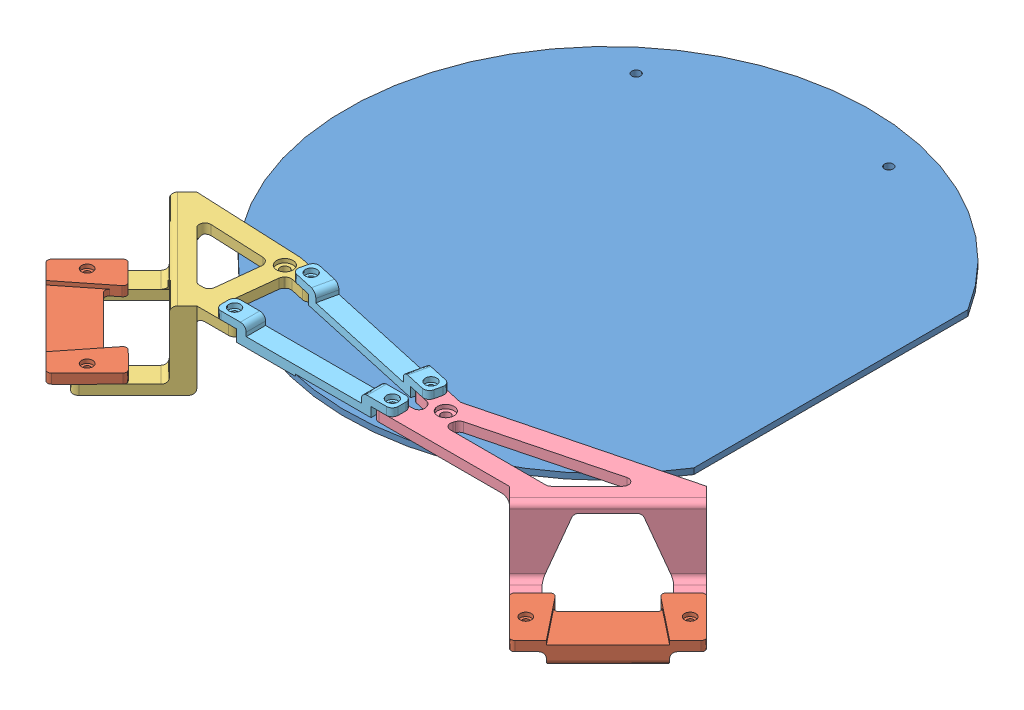
SolidWorks assembly CAMERA_MOUNT_ASSEMBLY, configuration Default. Lengths in mm.
Overall size (340.83 45.23 305.46).
7 component instances, 5 part files, 29 mates.
Components (placement in the parent):
- TURTLEBOT4_MOUNTING_PLATE-1: TURTLEBOT4_MOUNTING_PLATE [Default] at (92.0008 146.1427 210.8405) x (1 0 0) z (0 -1 0) size (250 270 3)
- CAMERA_SHELF-1: CAMERA_SHELF [Default] at (-42.3436 116.1427 345.2381) x (-0.707209 0 -0.707005) z (0.707005 0 -0.707209) size (72 11.23 30)
- CAMERA_SHELF-2: CAMERA_SHELF [Default] at (226.357 116.1427 345.1993) x (-0.707005 0 0.707209) z (-0.707209 0 -0.707005) size (72 11.23 30)
- CAMERA_MOUNT_RIGHT_PART_A-1: CAMERA_MOUNT_RIGHT_PART_A [Default] at (92.0008 146.1427 210.8704) x (0 0 -1) z (1 0 0) size (82.19 40 106.27)
- CAMERA_MOUNT_RIGHT_PART_B-1: CAMERA_MOUNT_RIGHT_PART_B [Default] at (92.0008 146.1427 210.8704) x (0 0 -1) z (1 0 0) size (82.2 40 152.52)
- CAMERA_MOUNT_RIGHT_PART_C-3: CAMERA_MOUNT_RIGHT_PART_C [Default] at (65.5792 145.1427 234.9517) x (-0.21658 0 -0.976265) z (0.976265 0 -0.21658) size (28.39 10 90.24)
- CAMERA_MOUNT_RIGHT_PART_C-4: CAMERA_MOUNT_RIGHT_PART_C [Default] at (91.0245 145.1427 210.6539) x (0 0 -1) z (1 0 0) size (28.39 10 90.24)
Mates (geometry in assembly coordinates):
- Concentric1: concentric aligned: cylinder of TURTLEBOT4_MOUNTING_PLATE-1 through (122.6303 143.1427 325.1511) axis (0 -1 0) radius 2.25; cylinder of CAMERA_MOUNT_RIGHT-1 through (122.6303 151.1427 325.1511) axis (0 -1 0) radius 2.35
- Concentric2: concentric aligned: cylinder of TURTLEBOT4_MOUNTING_PLATE-1 through (15.9314 143.1427 301.4966) axis (0 -1 0) radius 2.25; cylinder of CAMERA_MOUNT_RIGHT-1 through (15.9314 151.1427 301.4966) axis (0 -1 0) radius 2.35
- Coincident1: coincident anti-aligned: plane of TURTLEBOT4_MOUNTING_PLATE-1 through (92.0008 146.1427 210.8405) normal (0 1 0); plane of CAMERA_MOUNT_RIGHT-1 through (92.0008 146.1427 210.8704) normal (0 -1 0)
- Concentric3: concentric aligned: cylinder of CAMERA_MOUNT_RIGHT-1 through (205.1468 111.1427 366.4156) axis (0 1 0) radius 1.6; cylinder of CAMERA_SHELF-2 through (205.1468 109.9176 366.4156) axis (0 1 0) radius 1.6
- Concentric4: concentric aligned: cylinder of CAMERA_MOUNT_RIGHT-1 through (247.5671 111.1427 323.9831) axis (0 1 0) radius 1.6; cylinder of CAMERA_SHELF-2 through (247.5671 109.9176 323.9831) axis (0 1 0) radius 1.6
- Coincident2: coincident anti-aligned: plane of CAMERA_MOUNT_RIGHT-1 through (223.5208 116.1427 291.4596) normal (0 1 0); plane of CAMERA_SHELF-2 through (226.357 116.1427 345.1993) normal (0 -1 0)
- Concentric5: concentric aligned: cylinder of CAMERA_MOUNT_RIGHT-1 through (-21.1273 111.1427 366.4482) axis (0 1 0) radius 1.6; cylinder of CAMERA_SHELF-1 through (-21.1273 109.9176 366.4482) axis (0 1 0) radius 1.6
- Concentric6: concentric aligned: cylinder of CAMERA_MOUNT_RIGHT-1 through (-63.5598 111.1427 324.028) axis (0 1 0) radius 1.6; cylinder of CAMERA_SHELF-1 through (-63.5598 109.9176 324.028) axis (0 1 0) radius 1.6
- Coincident3: coincident anti-aligned: plane of CAMERA_MOUNT_RIGHT-1 through (-39.5229 116.1427 291.4976) normal (0 1 0); plane of CAMERA_SHELF-1 through (-42.3436 116.1427 345.2381) normal (0 -1 0)
- Concentric7: concentric aligned: cylinder of CAMERA_MOUNT_RIGHT_PART_A-1 through (30.0862 111.1427 302.0739) axis (0 1 0) radius 1.6; cylinder of CAMERA_MOUNT_RIGHT_PART_C-1 through (20.1187 145.1427 287.9629) axis (0 1 0) radius 1.6
- Coincident5: coincident anti-aligned: plane of CAMERA_MOUNT_RIGHT_PART_A-1 through (92.0008 151.1427 210.8704) normal (0 1 0); plane of CAMERA_MOUNT_RIGHT_PART_C-1 through (26.7977 151.1427 292.0116) normal (0 -1 0)
- Coincident6: coincident anti-aligned: plane of CAMERA_MOUNT_RIGHT_PART_B-1 through (92.0008 151.1427 210.8704) normal (0 1 0); plane of CAMERA_MOUNT_RIGHT_PART_C-1 through (49.359 151.1427 357.643) normal (0 -1 0)
- Concentric8: concentric aligned: cylinder of CAMERA_MOUNT_RIGHT_PART_B-1 through (109.5576 111.1427 319.6923) axis (0 1 0) radius 1.6; cylinder of CAMERA_MOUNT_RIGHT_PART_C-1 through (46.5811 145.1427 364.9425) axis (0 1 0) radius 1.6
- Concentric9: concentric aligned: cylinder of CAMERA_MOUNT_RIGHT_PART_A-1 through (25.8871 111.1427 337.3998) axis (0 1 0) radius 1.6; cylinder of CAMERA_MOUNT_RIGHT_PART_C-3 through (25.8871 145.1427 337.3998) axis (0 1 0) radius 1.6
- Concentric10: concentric aligned: cylinder of CAMERA_MOUNT_RIGHT_PART_B-1 through (107.288 111.1427 337.3881) axis (0 1 0) radius 1.6; cylinder of CAMERA_MOUNT_RIGHT_PART_C-3 through (107.288 145.1427 337.3881) axis (0 1 0) radius 1.6
- Coincident7: coincident anti-aligned: plane of CAMERA_MOUNT_RIGHT_PART_B-1 through (92.0008 151.1427 210.8704) normal (0 1 0); plane of CAMERA_MOUNT_RIGHT_PART_C-3 through (101.2873 151.1427 332.389) normal (0 -1 0)
- Coincident8: coincident anti-aligned: plane of TURTLEBOT4_MOUNTING_PLATE-1 through (92.0008 146.1427 210.8405) normal (0 1 0); plane of CAMERA_MOUNT_RIGHT_PART_A-1 through (92.0008 146.1427 210.8704) normal (0 -1 0)
- Concentric11: concentric aligned: cylinder of TURTLEBOT4_MOUNTING_PLATE-1 through (15.9314 143.1427 301.4966) axis (0 -1 0) radius 2.25; cylinder of CAMERA_MOUNT_RIGHT_PART_A-1 through (15.9314 151.1427 301.4966) axis (0 -1 0) radius 2.35
- Coincident9: coincident anti-aligned: plane of CAMERA_MOUNT_RIGHT_PART_A-1 through (92.0008 151.1427 210.8704) normal (0 1 0); plane of CAMERA_MOUNT_RIGHT_PART_C-3 through (31.8863 151.1427 332.399) normal (0 -1 0)
- Concentric13: concentric aligned: cylinder of TURTLEBOT4_MOUNTING_PLATE-1 through (122.6303 143.1427 325.1511) axis (0 -1 0) radius 2.25; cylinder of CAMERA_MOUNT_RIGHT_PART_B-1 through (122.6303 151.1427 325.1511) axis (0 -1 0) radius 2.35
- Coincident10: coincident anti-aligned: plane of CAMERA_MOUNT_RIGHT_PART_B-1 through (92.0008 151.1427 210.8704) normal (0 1 0); plane of CAMERA_MOUNT_RIGHT_PART_C-4 through (104.782 151.1427 313.5122) normal (0 -1 0)
- Concentric14: concentric aligned: cylinder of CAMERA_MOUNT_RIGHT_PART_B-1 through (109.5576 111.1427 319.6923) axis (0 1 0) radius 1.6; cylinder of CAMERA_MOUNT_RIGHT_PART_C-4 through (109.5576 145.1427 319.6923) axis (0 1 0) radius 1.6
- Concentric15: concentric aligned: cylinder of CAMERA_MOUNT_RIGHT_PART_A-1 through (30.0862 111.1427 302.0739) axis (0 1 0) radius 1.6; cylinder of CAMERA_MOUNT_RIGHT_PART_C-4 through (30.0862 145.1427 302.0739) axis (0 1 0) radius 1.6
- Coincident11: coincident anti-aligned: plane of CAMERA_SHELF-2 through (226.357 116.1427 345.1993) normal (0 -1 0); plane of CAMERA_MOUNT_RIGHT_PART_B-1 through (172.6165 116.1427 342.3787) normal (0 1 0)
- Concentric16: concentric aligned: cylinder of CAMERA_SHELF-2 through (205.1468 109.9176 366.4156) axis (0 1 0) radius 1.6; cylinder of CAMERA_MOUNT_RIGHT_PART_B-1 through (205.1468 111.1427 366.4156) axis (0 1 0) radius 1.6
- Concentric17: concentric aligned: cylinder of CAMERA_SHELF-2 through (247.5671 109.9176 323.9831) axis (0 1 0) radius 1.6; cylinder of CAMERA_MOUNT_RIGHT_PART_B-1 through (247.5671 111.1427 323.9831) axis (0 1 0) radius 1.6
- Concentric18: concentric aligned: cylinder of CAMERA_SHELF-1 through (-63.5598 109.9176 324.028) axis (0 1 0) radius 1.6; cylinder of CAMERA_MOUNT_RIGHT_PART_A-1 through (-63.5598 111.1427 324.028) axis (0 1 0) radius 1.6
- Concentric19: concentric aligned: cylinder of CAMERA_SHELF-1 through (-21.1273 109.9176 366.4482) axis (0 1 0) radius 1.6; cylinder of CAMERA_MOUNT_RIGHT_PART_A-1 through (-21.1273 111.1427 366.4482) axis (0 1 0) radius 1.6
- Coincident12: coincident anti-aligned: plane of CAMERA_SHELF-1 through (-42.3436 116.1427 345.2381) normal (0 -1 0); plane of CAMERA_MOUNT_RIGHT_PART_A-1 through (11.3961 116.1427 342.4019) normal (0 1 0)
